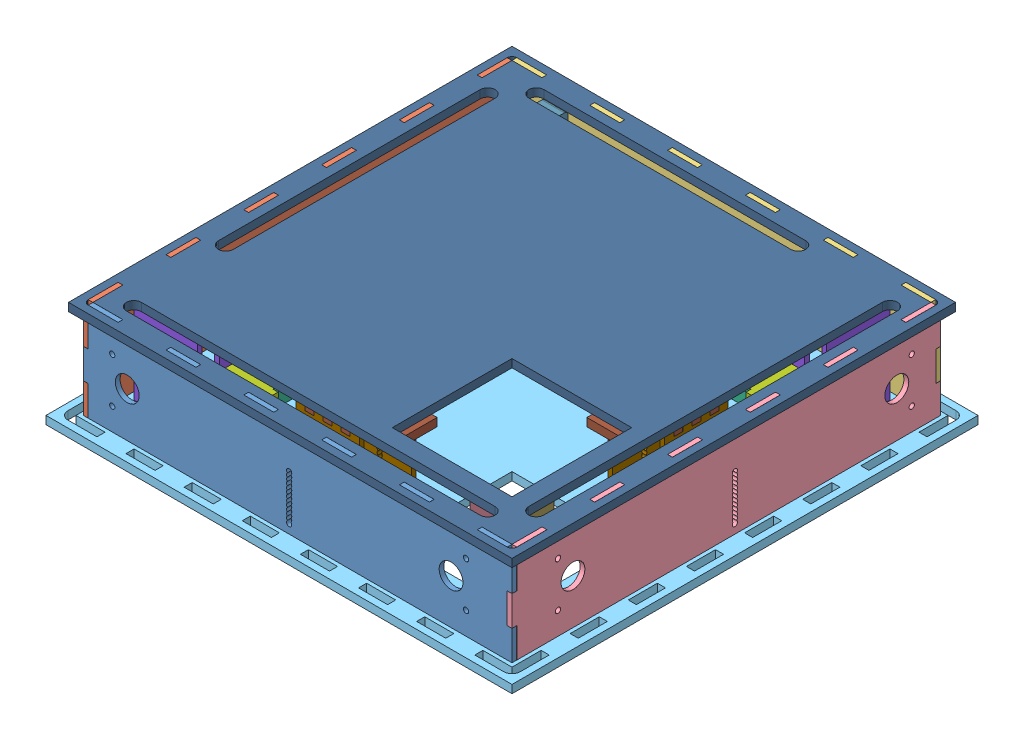
SolidWorks assembly stackerAssembly, configuration Default. Lengths in mm.
Overall size (311.48 71.79 311.52).
39 component instances, 14 part files, 145 mates.
Components (placement in the parent):
- Outer Wall_Horizontal To Elevator-3: Outer Wall_Horizontal To Elevator [Default] at (-269.6839 99.0364 51.1106) x (-1 0 0) z (0 0 -1) size (286.4 70.8 3.17)
- Outer Wall_Spinner To Horizontal-2: Outer Wall_Spinner To Horizontal [Default] at (-412.8689 99.0364 -92.0644) x (0 0 -1) z (1 0 0) size (286.4 70.8 3.17)
- Outer Wall_Spinner To Vertical-4: Outer Wall_Spinner To Vertical [Default] at (-269.6939 99.0364 -235.2894) size (286.4 70.8 3.17)
- Outer Wall_Vertical To Elevator-4: Outer Wall_Vertical To Elevator [Default] at (-126.4689 99.0364 -92.1044) x (0 0 1) z (-1 0 0) size (286.48 70.88 3.2)
- Testbench Bottom Plate-3: Testbench Bottom Plate [Default] at (-113.9689 63.6364 -247.7894) x (-1 0 0) z (0 0 -1) size (311.4 5.4 311.4)
- Stepper Platform Wall-2: Stepper Platform Wall [Default] at (-230.8439 69.0771 -188.4238) x (0 0 -1) z (1 0 0) size (36.03 14.36 3.17)
- Stepper Platform Wall-3: Stepper Platform Wall [Default] at (-209.6533 69.0771 -178.1394) size (36.03 14.36 3.17)
- Stepper Platform Wall-4: Stepper Platform Wall [Default] at (-191.7189 69.0771 -188.505) x (0 0 -1) z (1 0 0) size (36.03 14.36 3.17)
- Stepper Platform-2: Stepper Platform [Default] at (-209.6533 74.7114 -188.4238) x (0 0 -1) z (0 1 0) size (34.73 42.38 3.17)
- Stepper Holder-3: Stepper Holder [Default] at (-209.6939 99.0364 -209.6144) size (42.3 66.35 3.17)
- Middle Gear Holder-3: Middle Gear Holder [Default] at (-290.9439 90.1864 -209.6144) size (42.3 65.4 3.17)
- Stepper Platform Wall-5: Stepper Platform Wall [Default] at (-173.2533 69.0771 -187.9894) size (36.03 14.36 3.17)
- Stepper Platform Wall-6: Stepper Platform Wall [Default] at (-183.6189 69.0771 -206.005) x (0 0 1) z (-1 0 0) size (36.03 14.36 3.17)
- Stepper Platform Wall-7: Stepper Platform Wall [Default] at (-173.2533 69.0771 -227.1144) size (36.03 14.36 3.17)
- Stepper Platform Wall-8: Stepper Platform Wall [Default] at (-366.0033 69.0771 -53.2644) size (36.03 14.36 3.17)
- Stepper Platform Wall-9: Stepper Platform Wall [Default] at (-355.7189 69.0771 -32.0738) x (0 0 -1) z (1 0 0) size (36.03 14.36 3.17)
- Stepper Platform Wall-10: Stepper Platform Wall [Default] at (-366.0033 69.0771 -10.9644) x (-1 0 0) z (0 0 -1) size (36.03 14.36 3.17)
- Stepper Platform Wall-11: Stepper Platform Wall [Default] at (-365.5689 69.0771 4.245) x (0 0 -1) z (1 0 0) size (36.03 14.36 3.17)
- Stepper Platform Wall-12: Stepper Platform Wall [Default] at (-383.5033 69.0771 -9.2144) size (36.03 14.36 3.17)
- Stepper Platform Wall-13: Stepper Platform Wall [Default] at (-404.6939 69.0771 4.245) x (0 0 -1) z (1 0 0) size (36.03 14.36 3.17)
- Stepper Holder-5: Stepper Holder [Default] at (-152.1439 99.0364 -205.9644) x (0 0 1) z (-1 0 0) size (42.3 66.35 3.17)
- Stepper Holder-7: Stepper Holder [Default] at (-387.1939 99.0364 -32.1144) x (0 0 -1) z (1 0 0) size (42.3 66.35 3.17)
- Stepper Holder-8: Stepper Holder [Default] at (-383.5439 99.0364 22.2606) size (42.3 66.35 3.17)
- Middle Gear Holder-4: Middle Gear Holder [Default] at (-384.0189 90.1864 -113.3644) x (0 0 1) z (-1 0 0) size (42.3 65.4 3.17)
- Middle Gear Holder-5: Middle Gear Holder [Default] at (-275.3439 90.1864 22.2606) size (42.3 65.4 3.17)
- Middle Gear Holder-6: Middle Gear Holder [Default] at (-152.1439 90.1864 -97.7644) x (0 0 1) z (-1 0 0) size (42.3 65.4 3.17)
- Testbench Top Plate-1: Testbench Top Plate [Default] at (-121.4939 129.0364 -240.3144) x (-1 0 0) z (0 0 -1) size (296.4 5.4 296.4)
- Stepper Platform-3: Stepper Platform [Default] at (-366.0033 74.7114 -32.155) x (-1 0 0) z (0 1 0) size (34.73 42.38 3.17)
- Stepper Platform-4: Stepper Platform [Default] at (-383.5845 77.9471 4.2451) x (0 -0.003367 0.999994) z (0 -0.999994 -0.003367) size (34.73 42.38 3.17)
- Stepper Platform-5: Stepper Platform [Default] at (-173.3345 77.8864 -205.9238) x (1 0 0) z (0 -1 0) size (34.73 42.38 3.17)
- Bushing Holder-2: Bushing Holder [Default] at (-174.6425 120.1364 -89.1413) x (-1 0 0) z (0 0 -1) size (38 5.4 59.35)
- Bushing Holder-3: Bushing Holder [Default] at (-266.7636 120.1364 9.9342) x (0 0 1) z (-1 0 0) size (38 5.4 59.35)
- Middle Gear Holder-7: Middle Gear Holder [Default] at (-190.1439 90.1864 -97.7644) x (0 0 -1) z (1 0 0) size (42.3 65.4 3.17)
- Middle Gear Holder-8: Middle Gear Holder [Default] at (-275.3439 90.1864 -12.5644) size (42.3 65.4 3.17)
- Corner Holder pt1-1: Corner Holder pt1 [Default] at (-129.6439 69.0364 47.9356) size (3.18 65.4 28)
- Corner Holder pt2-2: Corner Holder pt2 [Default] at (-129.6939 69.0364 47.9356) size (28 65.4 3.18)
- Corner Holder pt1-2: Corner Holder pt1 [Default] at (-409.6939 69.0364 -183.9394) x (0 0 1) z (-1 0 0) size (3.18 65.4 28)
- Corner Holder pt2-3: Corner Holder pt2 [Default] at (-361.5189 69.0364 -232.1144) x (0 0 -1) z (1 0 0) size (28 65.4 3.18)
- Dowel Holder-1: Dowel Holder [Default] at (-387.1939 99.0914 -221.1144) x (0 0 -1) z (1 0 0) size (22 12.5 15)
Mates (geometry in assembly coordinates):
- Coincident53: coincident: line of Testbench Bottom Plate-3 through (-227.6689 69.0364 -190.4644) axis (0 0 1); plane of Stepper Platform Wall-2 through (-227.6689 69.0771 -188.4238) normal (1 0 0)
- Parallel24: parallel anti-aligned: line of Testbench Bottom Plate-3 through (-227.6689 69.0364 -190.4644) axis (0 0 1); line of Stepper Platform Wall-2 through (-227.6689 69.0364 -178.9644) axis (0 0 -1)
- Parallel25: parallel aligned: line of Testbench Bottom Plate-3 through (-230.8439 69.0364 -186.4644) axis (0 0 -1); line of Stepper Platform Wall-2 through (-230.8439 69.0364 -190.4644) axis (0 0 -1)
- Coincident56: coincident: plane of Testbench Bottom Plate-3 through (-113.9689 69.0364 -201.9644) normal (0 0 1); line of Stepper Platform Wall-2 through (-230.8439 63.6364 -201.9644) axis (0 1 0)
- Coincident57: coincident: plane of Testbench Bottom Plate-3 through (-113.9689 69.0364 -247.7894) normal (0 1 0); line of Stepper Platform Wall-2 through (-230.8439 69.0364 -170.4081) axis (0 0 -1)
- Coincident62: coincident: point of Testbench Bottom Plate-3; line of Stepper Platform Wall-4 through (-188.5439 69.0364 -197.9644) axis (0 -1 0)
- Coincident63: coincident anti-aligned: plane of Testbench Bottom Plate-3 through (-188.5439 69.0364 -247.7894) normal (-1 0 0); plane of Stepper Platform Wall-4 through (-188.5439 69.0771 -188.505) normal (1 0 0)
- Coincident85: coincident: line of Testbench Bottom Plate-3 through (-211.6939 69.0364 -206.4394) axis (0 0 -1); plane of Stepper Holder-3 through (-211.6939 99.0364 -206.4394) normal (-1 0 0)
- Coincident86: coincident: line of Testbench Bottom Plate-3 through (-207.6939 69.0364 -206.4394) axis (-1 0 0); plane of Stepper Holder-3 through (-209.6939 99.0364 -206.4394) normal (0 0 1)
- Coincident87: coincident: plane of Testbench Bottom Plate-3 through (-113.9689 69.0364 -247.7894) normal (0 1 0); line of Stepper Holder-3 through (-211.6939 69.0364 -206.4394) axis (-1 0 0)
- Coincident88: coincident: plane of Testbench Bottom Plate-3 through (-113.9689 69.0364 -247.7894) normal (0 1 0); line of Stepper Holder-3 through (-230.8439 69.0364 -206.4394) axis (0 0 -1)
- Coincident89: coincident: plane of Testbench Bottom Plate-3 through (-113.9689 69.0364 -247.7894) normal (0 1 0); line of Stepper Platform Wall-2 through (-227.6689 69.0364 -178.9644) axis (0 0 -1)
- Coincident111: coincident: line of Testbench Bottom Plate-3 through (-300.4439 69.0364 -206.4394) axis (-1 0 0); plane of Middle Gear Holder-3 through (-290.9439 90.1864 -206.4394) normal (0 0 1)
- Coincident131: coincident anti-aligned: plane of Testbench Bottom Plate-3 through (-113.9689 69.0364 -184.8144) normal (0 0 -1); plane of Stepper Platform Wall-5 through (-173.2533 69.0771 -184.8144) normal (0 0 1)
- Coincident132: coincident anti-aligned: plane of Testbench Bottom Plate-3 through (-163.7939 69.0364 -247.7894) normal (1 0 0); plane of Stepper Platform Wall-5 through (-163.7939 69.0364 -187.9894) normal (-1 0 0)
- Coincident135: coincident anti-aligned: plane of Testbench Bottom Plate-3 through (-113.9689 69.0364 -223.9394) normal (0 0 -1); plane of Stepper Platform Wall-7 through (-173.2533 69.0771 -223.9394) normal (0 0 1)
- Coincident136: coincident anti-aligned: plane of Testbench Bottom Plate-3 through (-163.7939 69.0364 -247.7894) normal (1 0 0); plane of Stepper Platform Wall-7 through (-163.7939 69.0364 -227.1144) normal (-1 0 0)
- Coincident139: coincident anti-aligned: plane of Testbench Bottom Plate-3 through (-113.9689 69.0364 -53.2644) normal (0 0 1); plane of Stepper Platform Wall-8 through (-366.0033 69.0771 -53.2644) normal (0 0 -1)
- Coincident140: coincident anti-aligned: plane of Testbench Bottom Plate-3 through (-379.5439 69.0364 -247.7894) normal (1 0 0); plane of Stepper Platform Wall-8 through (-379.5439 69.0364 -53.2644) normal (-1 0 0)
- Coincident141: coincident anti-aligned: plane of Testbench Bottom Plate-3 through (-113.9689 69.0364 -10.9644) normal (0 0 -1); plane of Stepper Platform Wall-10 through (-366.0033 69.0771 -10.9644) normal (0 0 1)
- Coincident143: coincident: plane of Testbench Bottom Plate-3 through (-379.5439 69.0364 -247.7894) normal (1 0 0); line of Stepper Platform Wall-10 through (-379.5439 63.6364 -10.9644) axis (0 1 0)
- Coincident144: coincident anti-aligned: plane of Testbench Bottom Plate-3 through (-365.5689 69.0364 -247.7894) normal (1 0 0); plane of Stepper Platform Wall-11 through (-365.5689 69.0771 4.245) normal (-1 0 0)
- Coincident145: coincident anti-aligned: plane of Testbench Bottom Plate-3 through (-113.9689 69.0364 -5.2144) normal (0 0 -1); plane of Stepper Platform Wall-11 through (-365.5689 69.0364 -5.2144) normal (0 0 1)
- Coincident148: coincident anti-aligned: plane of Testbench Bottom Plate-3 through (-401.5189 69.0364 -247.7894) normal (-1 0 0); plane of Stepper Platform Wall-13 through (-401.5189 69.0771 4.245) normal (1 0 0)
- Coincident149: coincident anti-aligned: plane of Testbench Bottom Plate-3 through (-113.9689 69.0364 -5.2144) normal (0 0 -1); plane of Stepper Platform Wall-13 through (-404.6939 69.0364 -5.2144) normal (0 0 1)
- Coincident150: coincident aligned: plane of Testbench Bottom Plate-3 through (-113.9689 63.6364 -247.7894) normal (0 -1 0); plane of Stepper Platform Wall-7 through (-163.7939 63.6364 -227.1144) normal (0 -1 0)
- Coincident152: coincident aligned: plane of Testbench Bottom Plate-3 through (-113.9689 63.6364 -247.7894) normal (0 -1 0); plane of Stepper Platform Wall-5 through (-186.7939 63.6364 -187.9894) normal (0 -1 0)
- Coincident159: coincident anti-aligned: plane of Testbench Bottom Plate-3 through (-113.9689 69.0364 25.4356) normal (0 0 -1); plane of Stepper Holder-8 through (-383.5439 99.0364 25.4356) normal (0 0 1)
- Coincident160: coincident anti-aligned: plane of Testbench Bottom Plate-3 through (-397.0439 69.0364 -247.7894) normal (1 0 0); plane of Stepper Holder-8 through (-397.0439 99.0364 25.4356) normal (-1 0 0)
- Coincident161: coincident anti-aligned: plane of Testbench Bottom Plate-3 through (-384.0189 69.0364 -247.7894) normal (-1 0 0); plane of Stepper Holder-7 through (-384.0189 99.0364 -32.1144) normal (1 0 0)
- Coincident162: coincident anti-aligned: plane of Testbench Bottom Plate-3 through (-113.9689 69.0364 -18.6144) normal (0 0 -1); plane of Stepper Holder-7 through (-384.0189 99.0364 -18.6144) normal (0 0 1)
- Coincident163: coincident anti-aligned: plane of Testbench Bottom Plate-3 through (-155.3189 69.0364 -247.7894) normal (1 0 0); plane of Stepper Holder-5 through (-155.3189 99.0364 -205.9644) normal (-1 0 0)
- Coincident164: coincident anti-aligned: plane of Testbench Bottom Plate-3 through (-113.9689 69.0364 -192.4644) normal (0 0 -1); plane of Stepper Holder-5 through (-155.3189 99.0364 -192.4644) normal (0 0 1)
- Coincident165: coincident anti-aligned: plane of Testbench Bottom Plate-3 through (-155.3189 69.0364 -247.7894) normal (1 0 0); plane of Stepper Holder-5 through (-155.3189 99.0364 -205.9644) normal (-1 0 0)
- Coincident169: coincident anti-aligned: plane of Testbench Bottom Plate-3 through (-387.1939 69.0364 -247.7894) normal (1 0 0); plane of Middle Gear Holder-4 through (-387.1939 90.1864 -113.3644) normal (-1 0 0)
- Coincident171: coincident anti-aligned: plane of Testbench Bottom Plate-3 through (-113.9689 69.0364 25.4356) normal (0 0 -1); plane of Middle Gear Holder-5 through (-275.3439 90.1864 25.4356) normal (0 0 1)
- Coincident173: coincident anti-aligned: plane of Testbench Bottom Plate-3 through (-152.1439 69.0364 -247.7894) normal (-1 0 0); plane of Middle Gear Holder-6 through (-152.1439 90.1864 -97.7644) normal (1 0 0)
- Coincident213: coincident: plane of Testbench Bottom Plate-3 through (-113.9689 69.0364 -99.8644) normal (0 0 -1); line of Middle Gear Holder-4 through (-384.0189 69.0364 -99.8644) axis (0 -1 0)
- Coincident214: coincident: plane of Testbench Bottom Plate-3 through (-113.9689 69.0364 -247.7894) normal (0 1 0); line of Middle Gear Holder-4 through (-384.0189 69.0364 -99.8644) axis (0 0 1)
- Coincident215: coincident: plane of Testbench Bottom Plate-3 through (-292.9439 69.0364 -247.7894) normal (1 0 0); line of Middle Gear Holder-3 through (-292.9439 63.6364 -209.6144) axis (0 1 0)
- Coincident216: coincident: plane of Testbench Bottom Plate-3 through (-113.9689 69.0364 -247.7894) normal (0 1 0); line of Middle Gear Holder-3 through (-312.0939 69.0364 -209.6144) axis (1 0 0)
- Coincident217: coincident: plane of Testbench Bottom Plate-3 through (-277.3439 69.0364 -247.7894) normal (1 0 0); line of Middle Gear Holder-5 through (-277.3439 63.6364 22.2606) axis (0 1 0)
- Coincident218: coincident: plane of Testbench Bottom Plate-3 through (-113.9689 69.0364 -247.7894) normal (0 1 0); line of Middle Gear Holder-5 through (-273.3439 69.0364 22.2606) axis (1 0 0)
- Coincident219: coincident: plane of Testbench Bottom Plate-3 through (-113.9689 69.0364 -95.7644) normal (0 0 -1); line of Middle Gear Holder-6 through (-152.1439 63.6364 -95.7644) axis (0 1 0)
- Coincident220: coincident: plane of Testbench Bottom Plate-3 through (-113.9689 69.0364 -247.7894) normal (0 1 0); line of Middle Gear Holder-6 through (-152.1439 69.0364 -95.7644) axis (0 0 1)
- Coincident221: coincident: plane of Outer Wall_Spinner To Horizontal-2 through (-412.8689 99.0364 -92.0644) normal (-1 0 0); line of Testbench Bottom Plate-3 through (-412.8689 69.0364 47.9356) axis (0 0 -1)
- Coincident222: coincident: plane of Outer Wall_Spinner To Horizontal-2 through (-409.6939 99.0364 27.9356) normal (0 0 -1); line of Testbench Bottom Plate-3 through (-409.6939 69.0364 27.9356) axis (-1 0 0)
- Coincident223: coincident: line of Outer Wall_Spinner To Horizontal-2 through (-412.8689 69.0364 27.9356) axis (0 0 -1); plane of Testbench Bottom Plate-3 through (-113.9689 69.0364 -247.7894) normal (0 1 0)
- Coincident227: coincident: plane of Outer Wall_Spinner To Vertical-4 through (-269.6939 99.0364 -235.2894) normal (0 0 -1); line of Testbench Bottom Plate-3 through (-389.6939 69.0364 -235.2894) axis (-1 0 0)
- Coincident228: coincident: line of Outer Wall_Spinner To Vertical-4 through (-389.6939 69.0364 -235.2894) axis (0 -1 0); plane of Testbench Bottom Plate-3 through (-389.6939 69.0364 -247.7894) normal (-1 0 0)
- Coincident229: coincident: line of Outer Wall_Spinner To Vertical-4 through (-389.6939 69.0364 -235.2894) axis (1 0 0); plane of Testbench Bottom Plate-3 through (-113.9689 69.0364 -247.7894) normal (0 1 0)
- Coincident230: coincident: plane of Testbench Bottom Plate-3 through (-113.9689 69.0364 -247.7894) normal (0 1 0); line of Stepper Holder-8 through (-374.0439 69.0364 25.4356) axis (-1 0 0)
- Coincident231: coincident: plane of Testbench Bottom Plate-3 through (-113.9689 69.0364 -247.7894) normal (0 1 0); line of Stepper Holder-7 through (-384.0189 69.0364 -30.1144) axis (0 0 1)
- Parallel43: parallel: plane of Testbench Bottom Plate-3 through (-113.9689 69.0364 2.2856) normal (0 0 1); line of Stepper Platform Wall-11 through (-362.3939 63.6364 2.2043) axis (0 1 0)
- Coincident234: coincident: plane of Testbench Bottom Plate-3 through (-113.9689 69.0364 -247.7894) normal (0 1 0); line of Stepper Platform Wall-11 through (-362.3939 69.0364 13.7043) axis (0 0 -1)
- Coincident235: coincident: plane of Testbench Bottom Plate-3 through (-113.9689 69.0364 -247.7894) normal (0 1 0); line of Stepper Platform Wall-13 through (-401.5189 69.0364 13.7043) axis (0 0 -1)
- Coincident237: coincident: plane of Testbench Bottom Plate-3 through (-113.9689 69.0364 -247.7894) normal (0 1 0); line of Stepper Platform Wall-10 through (-356.5439 69.0364 -10.9644) axis (-1 0 0)
- Coincident238: coincident: plane of Testbench Bottom Plate-3 through (-113.9689 69.0364 -247.7894) normal (0 1 0); line of Stepper Platform Wall-9 through (-352.5439 69.0364 -22.6144) axis (0 0 -1)
- Coincident239: coincident: plane of Testbench Bottom Plate-3 through (-113.9689 69.0364 -247.7894) normal (0 1 0); line of Stepper Platform Wall-8 through (-375.4626 69.0364 -50.0894) axis (1 0 0)
- Coincident240: coincident: plane of Testbench Bottom Plate-3 through (-113.9689 69.0364 -247.7894) normal (0 1 0); line of Stepper Holder-5 through (-152.1439 69.0364 -196.4644) axis (0 0 -1)
- Coincident241: coincident: plane of Testbench Bottom Plate-3 through (-113.9689 69.0364 -247.7894) normal (0 1 0); line of Stepper Platform Wall-4 through (-188.5439 69.0364 -179.0457) axis (0 0 -1)
- Coincident242: coincident: plane of Testbench Bottom Plate-3 through (-113.9689 69.0364 -247.7894) normal (0 1 0); line of Stepper Platform Wall-3 through (-219.1126 69.0364 -174.9644) axis (1 0 0)
- Coincident248: coincident: line of Stepper Holder-7 through (-384.0189 74.7114 -18.6144) axis (0 1 0); plane of Stepper Platform-3 through (-387.1939 74.7114 -18.6144) normal (0 0 1)
- Coincident249: coincident: line of Stepper Holder-7 through (-384.0189 77.8864 -18.6144) axis (0 0 -1); plane of Stepper Platform-3 through (-366.0033 77.8864 -32.155) normal (0 1 0)
- Coincident250: coincident: plane of Stepper Holder-7 through (-384.0189 99.0364 -32.1144) normal (1 0 0); line of Stepper Platform-3 through (-384.0189 77.8864 -30.1144) axis (0 0 1)
- Coincident251: coincident: line of Stepper Holder-8 through (-370.0439 74.7114 22.2606) axis (0 1 0); plane of Stepper Platform-4 through (-370.0439 77.8864 22.2606) normal (1 0 0)
- Coincident252: coincident: line of Stepper Holder-8 through (-374.0439 77.8864 22.2606) axis (1 0 0); plane of Stepper Platform-4 through (-383.5845 77.9471 4.2451) normal (0 0.999994 0.003367)
- Coincident253: coincident: plane of Stepper Holder-8 through (-383.5439 99.0364 22.2606) normal (0 0 -1); line of Stepper Platform-4 through (-374.1252 77.8864 22.2606) axis (-1 0 0)
- Coincident254: coincident: plane of Stepper Holder-5 through (-155.3189 99.0364 -219.4644) normal (0 0 1); line of Stepper Platform-5 through (-155.3189 77.8864 -219.4644) axis (1 0 0)
- Coincident255: coincident: line of Stepper Holder-5 through (-155.3189 77.8864 -219.4644) axis (0 0 1); plane of Stepper Platform-5 through (-173.3345 77.8864 -205.9238) normal (0 1 0)
- Coincident256: coincident: plane of Stepper Holder-5 through (-155.3189 99.0364 -205.9644) normal (-1 0 0); line of Stepper Platform-5 through (-155.3189 77.8864 -215.3831) axis (0 0 1)
- Coincident258: coincident: plane of Outer Wall_Horizontal To Elevator-3 through (-357.6839 99.0364 47.9356) normal (-1 0 0); line of Testbench Bottom Plate-3 through (-357.6839 69.0364 47.9356) axis (0 0 1)
- Coincident259: coincident aligned: plane of Outer Wall_Horizontal To Elevator-3 through (-269.6839 99.0364 51.1106) normal (0 0 1); line of Testbench Bottom Plate-3 through (-357.6839 69.0364 51.1106) axis (1 0 0)
- Coincident260: coincident: line of Outer Wall_Horizontal To Elevator-3 through (-357.6839 69.0364 51.1106) axis (-1 0 0); plane of Testbench Bottom Plate-3 through (-113.9689 69.0364 -247.7894) normal (0 1 0)
- Coincident261: coincident: plane of Outer Wall_Vertical To Elevator-4 through (-129.6439 99.0364 -160.1044) normal (0 0 1); line of Testbench Bottom Plate-3 through (-129.6439 69.0364 -160.1044) axis (1 0 0)
- Coincident262: coincident: plane of Outer Wall_Vertical To Elevator-4 through (-129.6439 99.0364 -92.1044) normal (-1 0 0); line of Testbench Bottom Plate-3 through (-129.6439 69.0364 -180.1044) axis (0 0 1)
- Coincident263: coincident: line of Outer Wall_Vertical To Elevator-4 through (-129.6439 69.0364 -160.1044) axis (0 0 1); plane of Testbench Bottom Plate-3 through (-113.9689 69.0364 -247.7894) normal (0 1 0)
- Coincident264: coincident: plane of Testbench Bottom Plate-3 through (-113.9689 69.0364 -247.7894) normal (0 1 0); line of Middle Gear Holder-3 through (-312.0939 69.0364 -206.4394) axis (0 0 -1)
- Parallel45: parallel anti-aligned: plane of Stepper Platform Wall-10 through (-352.4626 74.8177 -10.9644) normal (0 1 0); plane of Stepper Platform-3 through (-366.0033 74.7114 -32.155) normal (0 -1 0)
- Coincident267: coincident: line of Outer Wall_Vertical To Elevator-4 through (-126.4689 69.0364 -4.1044) axis (0 0 1); plane of Testbench Bottom Plate-3 through (-113.9689 69.0364 -247.7894) normal (0 1 0)
- Coincident268: coincident: line of Outer Wall_Horizontal To Elevator-3 through (-126.4839 69.0364 47.9356) axis (0 0 1); plane of Testbench Bottom Plate-3 through (-113.9689 69.0364 -247.7894) normal (0 1 0)
- Coincident273: coincident: line of Outer Wall_Spinner To Horizontal-2 through (-409.6939 69.0364 51.1356) axis (-1 0 0); plane of Testbench Bottom Plate-3 through (-113.9689 69.0364 -247.7894) normal (0 1 0)
- Parallel47: parallel aligned: line of Outer Wall_Spinner To Vertical-4 through (-126.4939 109.0364 -232.1144) axis (0 -1 0); line of Outer Wall_Vertical To Elevator-4 through (-126.4689 109.0364 -232.1044) axis (0 -1 0)
- Coincident279: coincident: line of Outer Wall_Spinner To Vertical-4 through (-409.6939 134.4364 -235.2894) axis (1 0 0); plane of Testbench Top Plate-1 through (-121.4939 134.4364 -235.2894) normal (0 0 1)
- Coincident280: coincident: line of Outer Wall_Spinner To Vertical-4 through (-389.6939 134.4364 -232.1144) axis (0 0 -1); plane of Testbench Top Plate-1 through (-389.6939 134.4364 -240.3144) normal (-1 0 0)
- Coincident282: coincident: plane of Outer Wall_Spinner To Horizontal-2 through (-409.6939 129.0364 -92.0644) normal (0 1 0); line of Testbench Top Plate-1 through (-417.8939 129.0364 56.0856) axis (0 0 -1)
- Coincident283: coincident: plane of Outer Wall_Horizontal To Elevator-3 through (-269.6839 129.0364 47.9356) normal (0 1 0); line of Testbench Top Plate-1 through (-121.4939 129.0364 56.0856) axis (-1 0 0)
- Coincident300: coincident: line of Testbench Bottom Plate-3 through (-352.5439 69.0364 -41.6144) axis (0 0 -1); plane of Stepper Platform Wall-9 through (-352.5439 69.0771 -32.0738) normal (1 0 0)
- Coincident301: coincident: plane of Testbench Bottom Plate-3 through (-113.9689 69.0364 -247.7894) normal (0 1 0); line of Stepper Platform Wall-9 through (-355.7189 69.0364 -14.0581) axis (1 0 0)
- Coincident303: coincident: line of Stepper Platform Wall-9 through (-355.7189 77.9927 -45.6144) axis (1 0 0); plane of Stepper Platform-3 through (-355.6376 74.7114 -45.6144) normal (0 0 1)
- Coincident305: coincident: plane of Stepper Platform Wall-2 through (-227.6689 69.0771 -188.4238) normal (1 0 0); line of Stepper Platform Wall-3 through (-227.6689 74.8177 -174.9644) axis (0 -1 0)
- Parallel48: parallel: plane of Testbench Bottom Plate-3 through (-113.9689 69.0364 -247.7894) normal (0 1 0); line of Stepper Platform Wall-3 through (-196.1126 63.6364 -178.1394) axis (0 0 1)
- Coincident307: coincident: line of Testbench Bottom Plate-3 through (-219.1939 69.0364 -174.9644) axis (-1 0 0); plane of Stepper Platform Wall-3 through (-209.6533 69.0771 -174.9644) normal (0 0 1)
- Coincident311: coincident: line of Stepper Platform-2 through (-219.1939 74.7114 -174.8831) axis (1 0 0); plane of Stepper Holder-3 through (-209.6939 74.7114 -206.4394) normal (0 1 0)
- Parallel50: parallel: line of Stepper Platform-2 through (-211.6939 77.8864 -209.6144) axis (0 0 1); plane of Stepper Holder-3 through (-211.6939 99.0364 -206.4394) normal (1 0 0)
- Coincident314: coincident: line of Stepper Platform-2 through (-211.6939 77.8864 -206.4394) axis (-1 0 0); plane of Stepper Holder-3 through (-209.6939 99.0364 -206.4394) normal (0 0 1)
- Parallel51: parallel aligned: line of Stepper Platform-2 through (-188.4626 74.7114 -190.3831) axis (0 0 -1); plane of Stepper Holder-3 through (-209.6939 74.7114 -206.4394) normal (0 1 0)
- Coincident316: coincident: line of Stepper Platform-2 through (-223.1939 77.8864 -209.6144) axis (0 0 1); plane of Stepper Holder-3 through (-223.1939 99.0364 -206.4394) normal (1 0 0)
- Coincident317: coincident: line of Testbench Bottom Plate-3 through (-186.7939 69.0364 -192.4644) axis (1 0 0); plane of Stepper Platform Wall-6 through (-183.6189 63.6364 -192.4644) normal (0 0 1)
- Parallel52: parallel: plane of Testbench Bottom Plate-3 through (-113.9689 69.0364 -219.4644) normal (0 0 1); line of Stepper Platform Wall-6 through (-186.7939 69.0364 -219.5457) axis (0 -1 0)
- Coincident319: coincident: line of Testbench Bottom Plate-3 through (-186.7939 69.0364 -219.4644) axis (0 0 1); plane of Stepper Platform Wall-6 through (-186.7939 69.0771 -206.005) normal (-1 0 0)
- Coincident320: coincident: plane of Testbench Bottom Plate-3 through (-113.9689 69.0364 -247.7894) normal (0 1 0); line of Stepper Platform Wall-6 through (-186.7939 69.0364 -215.4644) axis (0 0 1)
- Coincident321: coincident: plane of Testbench Bottom Plate-3 through (-113.9689 69.0364 -247.7894) normal (0 1 0); line of Stepper Platform Wall-6 through (-183.6189 69.0364 -224.0207) axis (0 0 1)
- Parallel53: parallel anti-aligned: plane of Stepper Platform Wall-6 through (-183.6189 74.8177 -208.0457) normal (0 1 0); plane of Stepper Platform-5 through (-173.3345 74.7114 -205.9238) normal (0 -1 0)
- Coincident323: coincident: plane of Testbench Bottom Plate-3 through (-397.0439 69.0364 -247.7894) normal (1 0 0); line of Stepper Platform Wall-12 through (-397.0439 69.0364 -9.2144) axis (0 -1 0)
- Coincident324: coincident: line of Testbench Bottom Plate-3 through (-397.0439 69.0364 -9.2144) axis (1 0 0); plane of Stepper Platform Wall-12 through (-383.5033 69.0771 -9.2144) normal (0 0 -1)
- Coincident325: coincident: plane of Testbench Bottom Plate-3 through (-113.9689 69.0364 -247.7894) normal (0 1 0); line of Stepper Platform Wall-12 through (-381.4626 69.0364 -9.2144) axis (1 0 0)
- Coincident326: coincident: plane of Testbench Bottom Plate-3 through (-113.9689 69.0364 -247.7894) normal (0 1 0); line of Stepper Platform Wall-12 through (-401.5189 69.0364 -6.0394) axis (1 0 0)
- Coincident327: coincident: plane of Stepper Platform Wall-12 through (-374.0439 74.8177 -9.2144) normal (0 1 0); line of Stepper Platform-4 through (-381.6252 74.8177 -9.3062) axis (1 0 0)
- Coincident331: coincident aligned: plane of Middle Gear Holder-5 through (-275.3439 90.1864 25.4356) normal (0 0 1); plane of Bushing Holder-3 through (-266.7636 125.5364 25.4356) normal (0 0 1)
- Coincident332: coincident: line of Middle Gear Holder-5 through (-266.2796 125.5364 25.4356) axis (1 0 0); plane of Bushing Holder-3 through (-266.7636 125.5364 9.9342) normal (0 1 0)
- Coincident333: coincident: moEndPointRef_w of Middle Gear Holder-5; line of Bushing Holder-3 through (-266.2796 125.5364 25.4356) axis (0 -1 0)
- Coincident334: coincident: line of Middle Gear Holder-6 through (-152.1439 125.5364 -82.6572) axis (0 -1 0); plane of Bushing Holder-2 through (-174.6425 125.5364 -82.6572) normal (0 0 1)
- Coincident335: coincident aligned: plane of Middle Gear Holder-6 through (-152.1439 90.1864 -97.7644) normal (1 0 0); plane of Bushing Holder-2 through (-152.1439 125.5364 -89.1413) normal (1 0 0)
- Coincident337: coincident: line of Middle Gear Holder-6 through (-152.1439 125.5364 -88.7001) axis (0 0 1); plane of Bushing Holder-2 through (-174.6425 125.5364 -89.1413) normal (0 1 0)
- Coincident338: coincident: line of Testbench Bottom Plate-3 through (-186.9689 69.0364 -111.2644) axis (-1 0 0); plane of Middle Gear Holder-7 through (-186.9689 90.1864 -111.2644) normal (0 0 -1)
- Coincident339: coincident: line of Testbench Bottom Plate-3 through (-190.1439 69.0364 -107.2644) axis (0 0 -1); plane of Middle Gear Holder-7 through (-190.1439 90.1864 -97.7644) normal (-1 0 0)
- Coincident340: coincident: plane of Testbench Bottom Plate-3 through (-113.9689 69.0364 -247.7894) normal (0 1 0); line of Middle Gear Holder-7 through (-190.1439 69.0364 -99.7644) axis (0 0 -1)
- Coincident341: coincident: plane of Testbench Bottom Plate-3 through (-113.9689 69.0364 -247.7894) normal (0 1 0); line of Middle Gear Holder-7 through (-186.9689 69.0364 -118.9144) axis (-1 0 0)
- Coincident342: coincident: line of Testbench Bottom Plate-3 through (-284.8439 69.0364 -12.5644) axis (-1 0 0); plane of Middle Gear Holder-8 through (-275.3439 90.1864 -12.5644) normal (0 0 -1)
- Coincident343: coincident: line of Testbench Bottom Plate-3 through (-288.8439 69.0364 -9.3894) axis (0 0 -1); plane of Middle Gear Holder-8 through (-288.8439 90.1864 -9.3894) normal (-1 0 0)
- Coincident344: coincident: plane of Testbench Bottom Plate-3 through (-113.9689 69.0364 -247.7894) normal (0 1 0); line of Middle Gear Holder-8 through (-284.8439 69.0364 -12.5644) axis (1 0 0)
- Coincident345: coincident: plane of Testbench Bottom Plate-3 through (-113.9689 69.0364 -247.7894) normal (0 1 0); line of Middle Gear Holder-8 through (-296.4939 69.0364 -9.3894) axis (0 0 -1)
- Coincident347: coincident: line of Testbench Bottom Plate-3 through (-155.3189 69.0364 14.7606) axis (0 0 1); plane of Corner Holder pt1-1 through (-155.3189 129.0364 47.9356) normal (-1 0 0)
- Coincident348: coincident: plane of Testbench Bottom Plate-3 through (-113.9689 69.0364 17.9356) normal (0 0 -1); line of Corner Holder pt1-1 through (-155.3189 63.6364 17.9356) axis (0 1 0)
- Coincident349: coincident: plane of Testbench Bottom Plate-3 through (-113.9689 69.0364 -247.7894) normal (0 1 0); line of Corner Holder pt1-1 through (-155.3189 69.0364 14.7606) axis (0 0 -1)
- Coincident350: coincident: plane of Testbench Bottom Plate-3 through (-113.9689 69.0364 -247.7894) normal (0 1 0); line of Corner Holder pt1-1 through (-152.1439 69.0364 -2.5644) axis (-1 0 0)
- Coincident353: coincident anti-aligned: plane of Testbench Bottom Plate-3 through (-170.3189 69.0364 -247.7894) normal (-1 0 0); plane of Corner Holder pt2-2 through (-170.3189 69.0364 22.2606) normal (1 0 0)
- Parallel54: parallel: plane of Testbench Bottom Plate-3 through (-159.6439 69.0364 -247.7894) normal (-1 0 0); line of Corner Holder pt2-2 through (-159.6939 63.6364 22.2606) axis (0 1 0)
- Coincident355: coincident: line of Testbench Bottom Plate-3 through (-162.8189 69.0364 22.2606) axis (1 0 0); plane of Corner Holder pt2-2 through (-129.6939 129.0364 22.2606) normal (0 0 -1)
- Coincident356: coincident: plane of Testbench Bottom Plate-3 through (-113.9689 69.0364 -247.7894) normal (0 1 0); line of Corner Holder pt2-2 through (-162.8189 69.0364 22.2606) axis (-1 0 0)
- Coincident357: coincident: plane of Testbench Bottom Plate-3 through (-113.9689 69.0364 -247.7894) normal (0 1 0); line of Corner Holder pt2-2 through (-180.1939 69.0364 25.4356) axis (0 0 -1)
- Coincident358: coincident: plane of Testbench Bottom Plate-3 through (-369.0189 69.0364 -247.7894) normal (1 0 0); line of Corner Holder pt1-2 through (-369.0189 63.6364 -206.4394) axis (0 1 0)
- Coincident359: coincident: plane of Testbench Bottom Plate-3 through (-379.6939 69.0364 -247.7894) normal (1 0 0); line of Corner Holder pt1-2 through (-379.6939 63.6364 -206.4394) axis (0 1 0)
- Coincident360: coincident: line of Testbench Bottom Plate-3 through (-376.5189 69.0364 -206.4394) axis (-1 0 0); plane of Corner Holder pt1-2 through (-409.6939 129.0364 -206.4394) normal (0 0 1)
- Coincident361: coincident: plane of Testbench Bottom Plate-3 through (-113.9689 69.0364 -247.7894) normal (0 1 0); line of Corner Holder pt1-2 through (-376.5189 69.0364 -206.4394) axis (1 0 0)
- Coincident362: coincident: plane of Testbench Bottom Plate-3 through (-113.9689 69.0364 -202.1144) normal (0 0 1); line of Corner Holder pt2-3 through (-384.0189 63.6364 -202.1144) axis (0 1 0)
- Parallel55: parallel: plane of Testbench Bottom Plate-3 through (-113.9689 69.0364 -191.4394) normal (0 0 1); line of Corner Holder pt2-3 through (-384.0189 63.6364 -191.4894) axis (0 1 0)
- Coincident365: coincident: line of Testbench Bottom Plate-3 through (-384.0189 69.0364 -188.2644) axis (0 0 -1); plane of Corner Holder pt2-3 through (-384.0189 129.0364 -232.1144) normal (1 0 0)
- Coincident366: coincident: plane of Testbench Bottom Plate-3 through (-113.9689 69.0364 -247.7894) normal (0 1 0); line of Corner Holder pt2-3 through (-384.0189 69.0364 -191.4894) axis (0 0 -1)
- Coincident367: coincident: plane of Testbench Bottom Plate-3 through (-113.9689 69.0364 -247.7894) normal (0 1 0); line of Corner Holder pt2-3 through (-384.0189 69.0364 -181.6144) axis (-1 0 0)
- Coincident368: coincident: plane of Testbench Bottom Plate-3 through (-113.9689 69.0364 -247.7894) normal (0 1 0); line of Corner Holder pt1-2 through (-359.1939 69.0364 -206.4394) axis (0 0 -1)
- Concentric1: concentric aligned: cylinder of Outer Wall_Spinner To Vertical-4 through (-382.1939 114.0364 -232.1144) axis (0 0 -1) radius 1.755; cylinder of Dowel Holder-1 through (-382.1939 114.0364 -202.1144) axis (0 0 -1) radius 1.755
- Coincident369: coincident: plane of Outer Wall_Spinner To Vertical-4 through (-269.6939 99.0364 -232.1144) normal (0 0 1); line of Dowel Holder-1 through (-372.1939 121.5914 -232.1144) axis (0 -1 0)
- Parallel56: parallel anti-aligned: plane of Testbench Bottom Plate-3 through (-113.9689 69.0364 -247.7894) normal (0 1 0); plane of Dowel Holder-1 through (-372.1939 111.5914 -221.1144) normal (0 -1 0)
